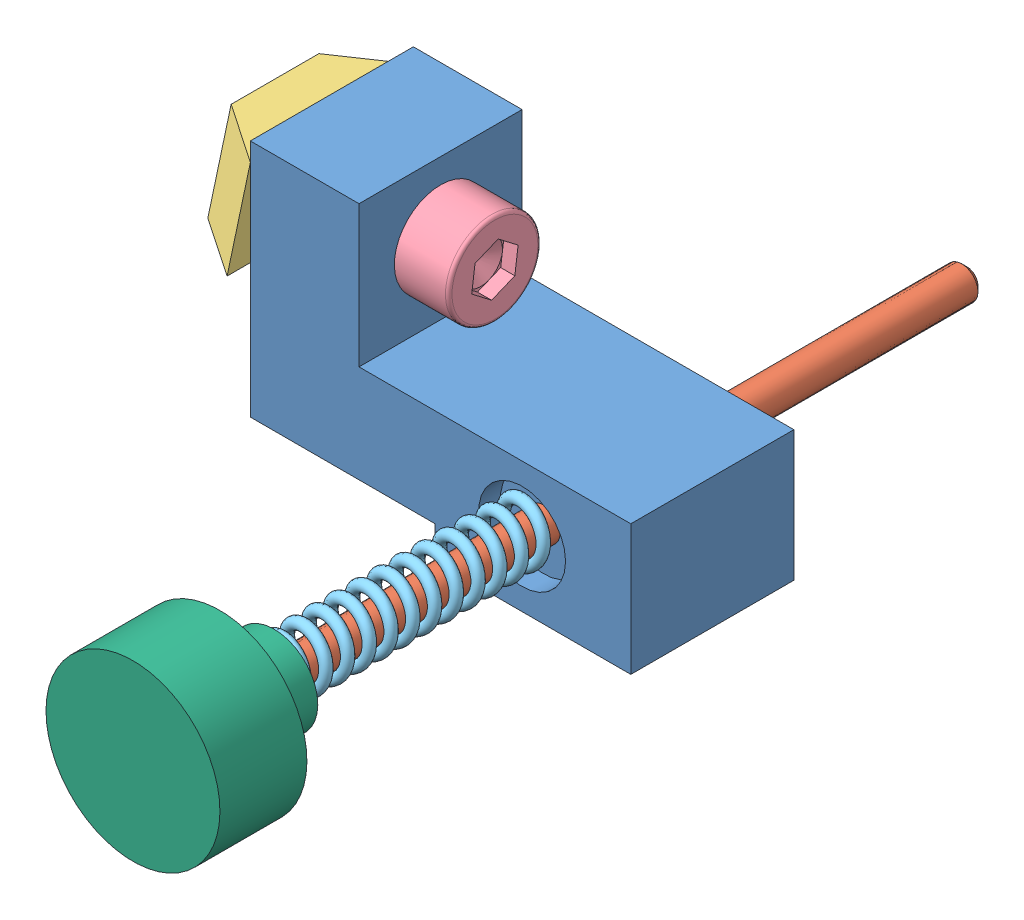
SolidWorks assembly Z_Endstop, configuration Default. Lengths in mm.
Overall size (41.3 28.47 76.73).
6 component instances, 6 part files, 5 mates.
Components (placement in the parent):
- Z_Endstop support-1: Z_Endstop support [Default] at (-54.6104 -6.2002 10.8203) size (35 25 15)
- M3x70-Threaded_Rod-1: M3x70-Threaded_Rod [Default] at (-29.6104 -0.2002 54.883) x (0.960118 0.279595 0) z (0 0 1) size (3 3 70)
- HNTF6-5-1: HNTF6-5 [Default] at (-54.6104 12.2998 18.3203) x (1 0 0) z (0 -0.965926 0.258819) size (6.3 15 12.3)
- Socket head cap screw-1: Socket head cap screw [M5x14] at (-39.6104 12.2998 18.3203) x (-1 0 0) z (0 -0.924225 -0.381849) size (19 8.5 8.5)
- spring-1: spring [Default] at (-30.1935 -0.3189 24.5904) x (1 0 0) z (0 -1 0) size (5.81 26.29 5.77)
- Z_Endstop knob-1: Z_Endstop knob [Default] at (-29.6104 -0.2002 61.6144) x (-0.999945 0.010474 0) z (0 0 -1) size (16 16 13)
Mates (geometry in assembly coordinates):
- Concentric1: concentric aligned: cylinder of Z_Endstop support-1 through (-29.6104 -0.2002 25.8203) axis (0 0 1) radius 1.25; cylinder of M3x70-Threaded_Rod-1 through (-29.6104 -0.2002 -15.117) axis (0 0 1) radius 1.5
- Concentric2: concentric aligned: cylinder of Z_Endstop support-1 through (-59.6104 12.2998 18.3203) axis (1 0 0) radius 2.65; cylinder of Socket head cap screw-1 through (-7.8604 12.2998 18.3203) axis (1 0 0) radius 2.5
- Coincident1: coincident aligned: plane of Z_Endstop support-1 through (-44.6104 5.7998 25.8203) normal (1 0 0); circle of Socket head cap screw-1
- Concentric3: concentric anti-aligned: cylinder of HNTF6-5-1 through (-60.9104 12.2998 18.3203) axis (-1 0 0) radius 2.067; cylinder of Socket head cap screw-1 through (-7.8604 12.2998 18.3203) axis (1 0 0) radius 2.5
- Concentric4: concentric anti-aligned: cylinder of M3x70-Threaded_Rod-1 through (-29.6104 -0.2002 -15.117) axis (0 0 1) radius 1.5; circle of Z_Endstop knob-1
